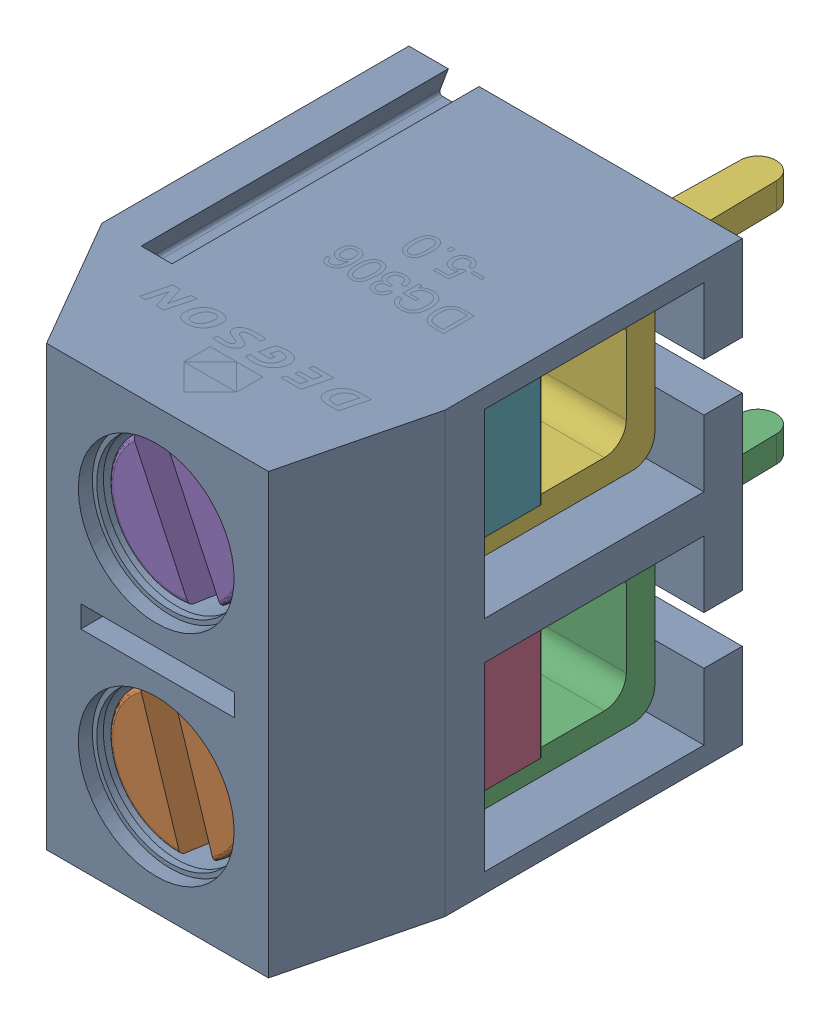
SolidWorks assembly DG306-5 v2 (1), configuration Predeterminado. Lengths in mm.
Overall size (7.6 10.62 14.13).
7 component instances, 4 part files, 0 mates.
Components (placement in the parent):
- Case (1)-1: Case (1) [Predeterminado] at (38.5 -16 0) x (0 1 0) z (1 0 0) size (10.62 10 7.6)
- Screw (1)-1: Screw (1) [Predeterminado] at (35.14 -13.5 3.88) x (-0.304322 0.952569 0) z (0.952569 0.304322 0) size (3.38 5.66 3.38)
- Terminal (1)-1: Terminal (1) [Predeterminado] at (32.9 -15.45 0.874) x (0 1 0) z (1 0 0) size (3.9 9.8 4.48)
- Spring (1)-1: Spring (1) [Predeterminado] at (37.5 -14.865 3.774) x (0 1 0) z (1 0 0) size (2.73 2.2 5.76)
- Screw (1)-2: Screw (1) [Predeterminado] at (35.14 -8.5 3.88) x (-0.425528 0.904945 0) z (0.904945 0.425528 0) size (3.38 5.66 3.38)
- Terminal (1)-2: Terminal (1) [Predeterminado] at (32.9 -10.45 0.874) x (0 1 0) z (1 0 0) size (3.9 9.8 4.48)
- Spring (1)-2: Spring (1) [Predeterminado] at (37.5 -9.865 3.774) x (0 1 0) z (1 0 0) size (2.73 2.2 5.76)
